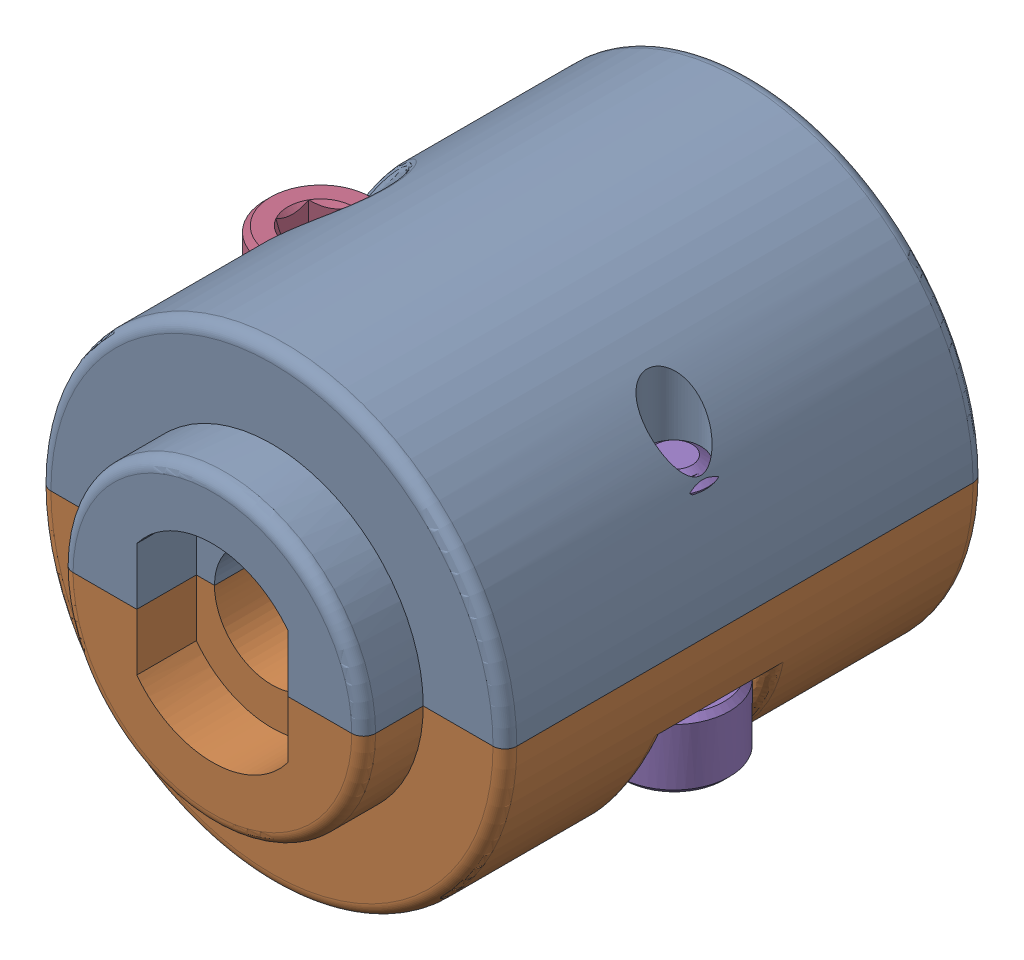
SolidWorks assembly 217-3195-200 Rev1, configuration Default. Lengths in mm.
Overall size (20.44 19.56 22.68).
5 component instances, 3 part files, 0 mates.
Components (placement in the parent):
- 217-3195-010 Rev1-1: 217-3195-010 Rev1 [Default] x (-1 0 0) z (0 0 1) size (19.61 11.78 22.68)
- 217-3195-010 Rev1-2: 217-3195-010 Rev1 [Default] at origin size (19.61 11.78 22.68)
- 217-2778-NCQ8A075-050M_1032_Nut_90545A111-1: 217-2778-NCQ8A075-050M_1032_Nut_90545A111 [Default] at (0 0 2.5527) x (-0.5 0.866025 0) z (0 0 1) size (9.53 11 3.39)
- 91251A107_91251A107_1-1: 91251A107_91251A107_1 [Default] at (-7.4168 -4.9375 -0.635) x (1 0 0) z (0 -1 0) size (4.65 4.65 10.79)
- 91251A107_91251A107_1-2: 91251A107_91251A107_1 [Default] at (7.4168 4.9375 -0.635) x (-0.837169 0 -0.546944) z (0 1 0) size (4.65 4.65 10.79)
